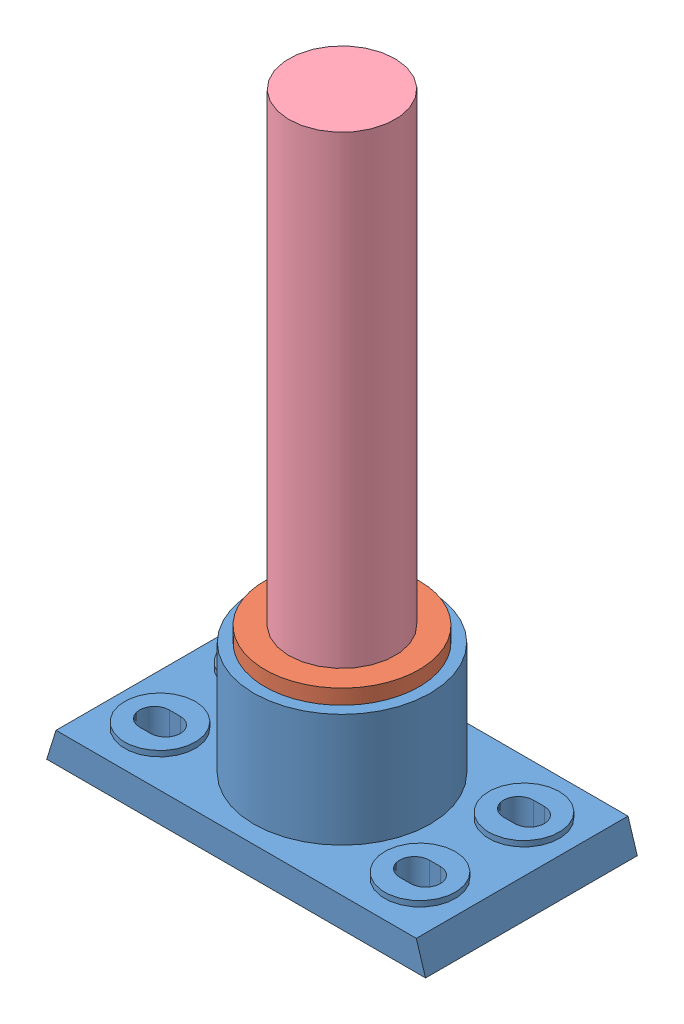
SolidWorks assembly Assem1, configuration Default. Lengths in mm.
Overall size (204 335 114).
4 component instances, 4 part files, 8 mates.
Components (placement in the parent):
- Part2-1: Part2 [Default] at (96.6526 66.5678 146.712) size (204 77 114)
- bush-2: bush [Default] at (96.6526 74.5678 146.712) size (83 77 83)
- pad-1: pad [Default] at (96.6526 82.5678 146.712) size (45.5 16.02 44)
- shaft-1: shaft [Default] at (96.6526 76.5678 146.712) x (-0.96647 0 -0.256781) z (0.256781 0 -0.96647) size (57 325 57)
Mates (geometry in assembly coordinates):
- Concentric2: concentric anti-aligned: cylinder of Part2-1 through (96.6526 82.5678 146.712) axis (0 1 0) radius 31; cylinder of bush-2 through (96.6526 -11.3051 146.712) axis (0 -1 0) radius 31
- Concentric9: concentric anti-aligned: cylinder of Part2-1 through (74.6526 77.5678 146.712) axis (0 1 0) radius 1.5; cylinder of bush-2 through (74.6526 79.5678 146.712) axis (0 -1 0) radius 1.5
- Coincident4: coincident anti-aligned: plane of Part2-1 through (49.1526 143.5678 203.712) normal (0 1 0); plane of bush-2 through (58.6526 143.5678 146.712) normal (0 -1 0)
- Concentric10: concentric anti-aligned: cylinder of pad-1 through (74.6526 87.5678 146.712) axis (0 -1 0) radius 1.5; cylinder of Part2-1 through (74.6526 77.5678 146.712) axis (0 1 0) radius 1.5
- Coincident5: coincident anti-aligned: plane of Part2-1 through (96.6526 82.5678 146.712) normal (0 1 0); plane of pad-1 through (96.6526 82.5678 146.712) normal (0 -1 0)
- Concentric11: concentric aligned: cylinder of bush-2 through (96.6526 -11.3051 146.712) axis (0 -1 0) radius 22; cylinder of pad-1 through (96.6526 82.5678 146.712) axis (0 -1 0) radius 22
- Concentric12: concentric aligned: cylinder of bush-2 through (96.6526 -11.3051 146.712) axis (0 -1 0) radius 22; cylinder of shaft-1 through (96.6526 -0.8879 146.712) axis (0 -1 0) radius 22
- Coincident6: coincident anti-aligned: plane of bush-2 through (55.1526 151.5678 146.712) normal (0 1 0); plane of shaft-1 through (117.915 151.5678 152.3612) normal (0 -1 0)
